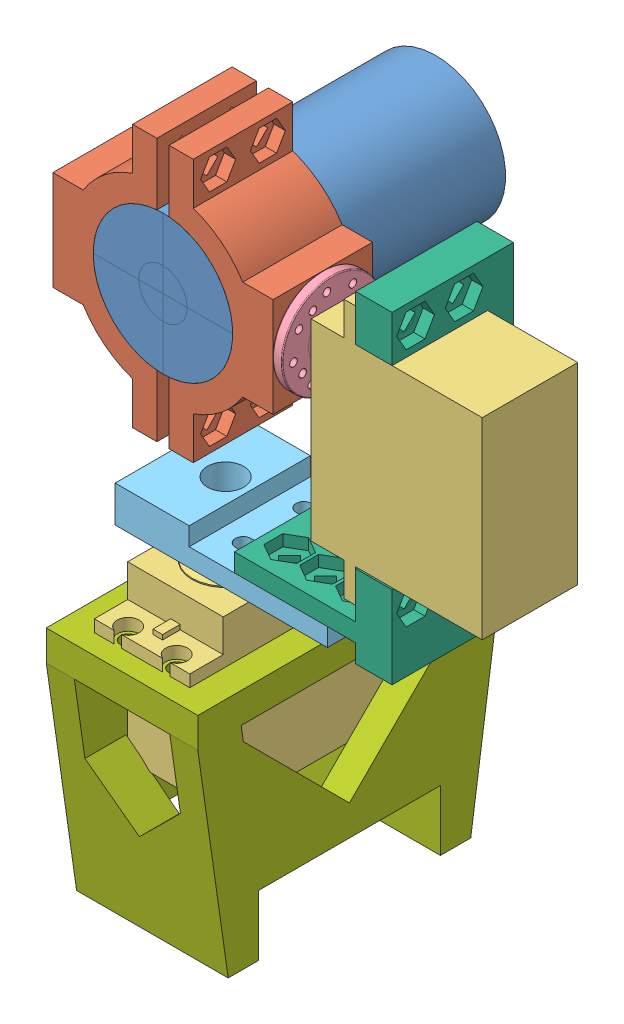
SolidWorks assembly CompleteAssembly, configuration Default. Lengths in mm.
Overall size (89.51 142.63 65.71).
13 component instances, 7 part files, 23 mates.
Components (placement in the parent):
- Microsoft Lifecam-1: Microsoft Lifecam [Default] at (-0.0005 89.712 -57.15) size (29.21 29.21 57.15)
- CameraHolder-1: CameraHolder [Default] at (-0.0005 89.712 -10.414) size (21.78 55.05 20.83)
- CameraHolder-2: CameraHolder [Default] at (-0.0005 89.712 -10.414) x (-1 0 0) z (0 0 -1) size (21.78 55.05 20.83)
- ServoAssembly-1: ServoAssembly [Default] at (73.1094 113.5509 -33.5433) x (0 0 1) z (0 -1 0) size (29.07 43.4 54.3)
  - S3151-1: S3151 [Default] at (23.1293 24.5802 33.4889) size (20 41.85 54.3)
  - servohorn-1: servohorn [Default] at (23.1293 50.0552 23.8389) x (-0.837169 0 -0.546944) z (-0.546944 0 0.837169) size (21 5.8 21)
- ServoAssembly-2: ServoAssembly [Default] at (23.1293 -7.7552 10.7249) x (-1 0 0) z (0 0 -1) size (29.07 43.4 54.3)
  - S3151-1: S3151 [Default] at (23.1293 24.5802 33.4889) size (20 41.85 54.3)
  - servohorn-1: servohorn [Default] at (23.1293 50.0552 23.8389) x (-0.837169 0 -0.546944) z (-0.546944 0 0.837169) size (21 5.8 21)
- YawArmAssembly-1: YawArmAssembly [Default] at (11.811 42.3 -13.114) size (57.99 67.56 25.4) (flexible)
  - YawArm-YawServoAttachment-1: YawArm-YawServoAttachment [Default] at origin size (44.45 7.62 25.4)
  - YawArm-PitchServoAttachment-1: YawArm-PitchServoAttachment [Default] at (28.1432 7.62 0) x (1 0 0) z (0 -1 0) size (33.02 25.4 67.56)
- WallPlate-1: WallPlate [Default] at (0 22.225 -23.188) size (31.75 50.8 63.5)
Mates (geometry in assembly coordinates):
- Concentric1: concentric aligned: cylinder of Microsoft Lifecam-1 through (-0.0005 89.712 0) axis (0 0 -1) radius 14.605; cylinder of CameraHolder-1 through (-0.0005 89.712 0) axis (0 0 -1) radius 14.605
- Concentric2: concentric anti-aligned: cylinder of Microsoft Lifecam-1 through (-0.0005 89.712 0) axis (0 0 -1) radius 14.605; cylinder of CameraHolder-2 through (-0.0005 89.712 -20.828) axis (0 0 1) radius 14.605
- Parallel1: parallel anti-aligned: plane of CameraHolder-1 through (-1.2705 71.0793 0) normal (1 0 0); plane of CameraHolder-2 through (1.2695 71.0793 -20.828) normal (-1 0 0)
- Coincident1: coincident aligned: plane of CameraHolder-1 through (-0.0005 89.712 0) normal (0 0 1); plane of CameraHolder-2 through (-0.0005 89.712 0) normal (0 0 1)
- Coincident2: coincident aligned: plane of CameraHolder-2 through (-0.0005 89.712 0) normal (0 0 1); plane of Microsoft Lifecam-1 through (-0.0005 89.712 0) normal (0 0 1)
- Concentric3: concentric aligned: circle of CameraHolder-2; circle of ServoAssembly-1/servohorn-1
- Coincident5: coincident anti-aligned: plane of CameraHolder-2 through (23.0542 100.126 -20.828) normal (1 0 0); plane of ServoAssembly-1/servohorn-1 through (23.0542 89.712 -10.414) normal (-1 0 0)
- Parallel4: parallel anti-aligned: line of Microsoft Lifecam-1 through (14.6045 89.712 0) axis (-1 0 0); line of CameraHolder-2 through (16.7042 79.298 0) axis (1 0 0)
- Concentric4: concentric anti-aligned: circle of ServoAssembly-2/servohorn-1; circle of ?
- Coincident6: coincident anti-aligned: plane of ServoAssembly-1/S3151-1; plane of ? through (-33.8426 62.62 -53.9942) normal (-0.025036 0 -0.999687)
- Coincident7: coincident anti-aligned: plane of ServoAssembly-1/S3151-1; plane of ? through (-34.3433 122.564 -73.9879) normal (0.999687 0 -0.025036)
- Coincident9: coincident anti-aligned: plane of ServoAssembly-1/S3151-1 through (-60.835 72.272 -73.3245) normal (0 -1 0); plane of ? through (-33.8426 72.272 -53.9942) normal (0 1 0)
- Coincident10: coincident anti-aligned: plane of ServoAssembly-2/servohorn-1 through (0 55 -62.144) normal (0 1 0); plane of ? through (10.0928 55 -75.1007) normal (0 -1 0)
- Coincident19: coincident anti-aligned: plane of ServoAssembly-2/S3151-1 through (-10 16.825 -22.764) normal (-1 0 0); plane of WallPlate-1 through (-10 19.05 -43.508) normal (1 0 0)
- Concentric6: concentric aligned: cylinder of ServoAssembly-2/S3151-1 through (5.08 -1.1 2.212) axis (0 1 0) radius 2.3; cylinder of WallPlate-1 through (5.08 19.05 2.212) axis (0 1 0) radius 1.632
- Coincident20: coincident anti-aligned: plane of ServoAssembly-2/servohorn-1; plane of YawArmAssembly-1/YawArm-YawServoAttachment-1
- Concentric7: concentric aligned: cylinder of ServoAssembly-2/servohorn-1 through (0 41.3 -13.114) axis (0 1 0) radius 3; cylinder of YawArmAssembly-1/YawArm-YawServoAttachment-1 through (0 42.3 -13.114) axis (0 1 0) radius 3.81
- Coincident21: coincident anti-aligned: plane of ServoAssembly-1/S3151-1 through (39.9542 107.212 -20.414) normal (1 0 0); plane of YawArmAssembly-1/YawArm-PitchServoAttachment-1 through (39.9542 109.864 -0.414) normal (-1 0 0)
- Coincident22: coincident anti-aligned: plane of ServoAssembly-1/S3151-1 through (48.5292 80.062 -20.414) normal (0 0 -1); plane of YawArmAssembly-1/YawArm-PitchServoAttachment-1 through (39.9542 49.92 -20.414) normal (0 0 1)
- Parallel5: parallel aligned: plane of YawArmAssembly-1/YawArm-YawServoAttachment-1 through (11.811 42.3 -0.414) normal (0 0 1); plane of WallPlate-1 through (0 22.225 8.562) normal (0 0 1)
- Coincident23: coincident aligned: plane of Microsoft Lifecam-1 through (-0.0005 89.712 0) normal (0 0 1); plane of assembly through (0 0 0) normal (0 0 1)
- Coincident24: coincident anti-aligned: plane of ServoAssembly-2/S3151-1; plane of WallPlate-1
- Concentric8: concentric aligned: circle of ServoAssembly-1/S3151-1; circle of YawArmAssembly-1/YawArm-PitchServoAttachment-1
